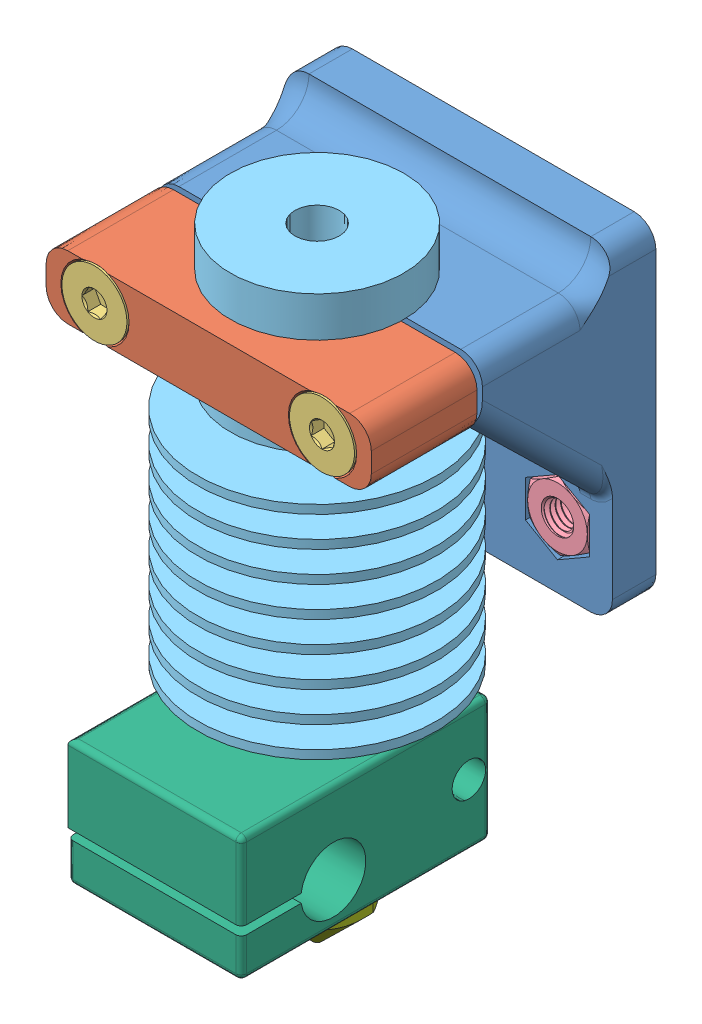
SolidWorks assembly Hotend Mount Assem, configuration Default . Lengths in mm.
Overall size (30 57.2 31.25).
11 component instances, 7 part files, 24 mates.
Components (placement in the parent):
- RearPart-1: RearPart [Default] at origin size (30 30 16)
- FrontPart-1: FrontPart [Default] at (0 9.075 21.375) size (30 5.85 9.75)
- M3x25 92125A138_TYPE 18-8 SS FLAT-HEAD SOCKET CAP SCREW-1: M3x25 92125A138_TYPE 18-8 SS FLAT-HEAD SOCKET CAP SCREW [92125A138] at (-10.4974 9.075 26.3) x (-0.848151 0.529754 0) z (0 0 1)
- M3x25 92125A138_TYPE 18-8 SS FLAT-HEAD SOCKET CAP SCREW-2: M3x25 92125A138_TYPE 18-8 SS FLAT-HEAD SOCKET CAP SCREW [92125A138] at (10.4974 9.075 26.3)
- 94150A325_TYPE 316 STAINLESS STEEL HEX NUT-1: 94150A325_TYPE 316 STAINLESS STEEL HEX NUT [94150A325] at (10.4974 9.075 3.8) x (0.5 -0.866025 0) z (0 0 1)
- 94150A325_TYPE 316 STAINLESS STEEL HEX NUT-2: 94150A325_TYPE 316 STAINLESS STEEL HEX NUT [94150A325] at (-10.4974 9.075 3.8)
- Lite6HeatSink-1: Lite6HeatSink [Default] at (0 -5.65 16.25) size (22 42.7 22)
- 94150A325_TYPE 316 STAINLESS STEEL HEX NUT-3: 94150A325_TYPE 316 STAINLESS STEEL HEX NUT [94150A325] at (9.925 -8.95 2.8)
- 94150A325_TYPE 316 STAINLESS STEEL HEX NUT-4: 94150A325_TYPE 316 STAINLESS STEEL HEX NUT [94150A325] at (-9.925 -8.95 2.8) x (0.5 0.866025 0) z (0 0 1)
- Heater Block-1: Heater Block [Default] at (0 -33.5 19.75) x (0 0 -1) z (1 0 0) size (23 11.5 16)
- MK8 nozzle 0,4mm-2: MK8 nozzle 0,4mm [Default] at (0 -33.5 16.25) x (-0.795741 0 0.605637) z (0.605637 0 0.795741)
Mates (geometry in assembly coordinates):
- Concentric1: concentric aligned: cylinder of RearPart-1 through (0 28.9706 16.25) axis (0 -1 0) radius 6; cylinder of FrontPart-1 through (0 12 16.25) axis (0 -1 0) radius 6
- Concentric2: concentric aligned: cylinder of RearPart-1 through (10.4974 9.075 16) axis (0 0 1) radius 1.8; cylinder of FrontPart-1 through (10.4974 9.075 26.25) axis (0 0 1) radius 1.8
- Coincident5: coincident aligned: cone of FrontPart-1 through (-10.4974 9.075 26.25) axis (0 0 -1); cone of M3x25 92125A138_TYPE 18-8 SS FLAT-HEAD SOCKET CAP SCREW-1 through (-10.4974 9.075 24.6) axis (0 0 -1)
- Coincident6: coincident aligned: cone of FrontPart-1 through (10.4974 9.075 26.25) axis (0 0 -1); cone of M3x25 92125A138_TYPE 18-8 SS FLAT-HEAD SOCKET CAP SCREW-2 through (10.4974 9.075 24.6) axis (0 0 -1)
- Concentric5: concentric anti-aligned: circle of RearPart-1; circle of 94150A325_TYPE 316 STAINLESS STEEL HEX NUT-1
- Coincident7: coincident anti-aligned: plane of RearPart-1 through (0 0 5) normal (0 0 -1); plane of 94150A325_TYPE 316 STAINLESS STEEL HEX NUT-1 through (10.4974 12.2504 5) normal (0 0 1)
- Parallel1: parallel anti-aligned: plane of RearPart-1 through (13.4474 10.7782 5) normal (-0.5 -0.866025 0); plane of 94150A325_TYPE 316 STAINLESS STEEL HEX NUT-1 through (13.2474 10.6627 5) normal (0.5 0.866025 0)
- Concentric6: concentric anti-aligned: circle of 92125A138_TYPE 18-8 SS FLAT-HEAD SOCKET CAP SCREW-1; circle of 94150A325_TYPE 316 STAINLESS STEEL HEX NUT-2
- Coincident8: coincident anti-aligned: plane of RearPart-1 through (0 0 5) normal (0 0 -1); plane of 94150A325_TYPE 316 STAINLESS STEEL HEX NUT-2 through (-13.2474 10.6627 5) normal (0 0 1)
- Parallel2: parallel anti-aligned: plane of RearPart-1 through (-13.4474 10.7782 5) normal (0.5 -0.866025 0); plane of 94150A325_TYPE 316 STAINLESS STEEL HEX NUT-2 through (-10.4974 12.2504 5) normal (-0.5 0.866025 0)
- Concentric7: concentric aligned: cylinder of RearPart-1 through (0 28.9706 16.25) axis (0 -1 0) radius 6; cylinder of Lite6HeatSink-1 through (0 -27 16.25) axis (0 -1 0) radius 6
- Coincident9: coincident anti-aligned: plane of RearPart-1 through (0 12 16) normal (0 1 0); plane of Lite6HeatSink-1 through (8 12 16.25) normal (0 -1 0)
- Concentric9: concentric anti-aligned: cylinder of RearPart-1 through (9.925 -8.95 4) axis (0 0 1) radius 1.8; circle of 94150A325_TYPE 316 STAINLESS STEEL HEX NUT-3
- Parallel3: parallel anti-aligned: plane of 94150A325_TYPE 316 STAINLESS STEEL HEX NUT-3 through (12.675 -7.3623 4) normal (0.5 0.866025 0); plane of RearPart-1 through (0.0808 0.1399 1.6) normal (-0.5 -0.866025 0)
- Coincident11: coincident anti-aligned: plane of RearPart-1 through (0 0 1.6) normal (0 0 1); plane of 94150A325_TYPE 316 STAINLESS STEEL HEX NUT-3 through (7.175 -7.3623 1.6) normal (0 0 -1)
- Concentric10: concentric anti-aligned: cylinder of RearPart-1 through (-9.925 -8.95 4) axis (0 0 1) radius 1.8; circle of 94150A325_TYPE 316 STAINLESS STEEL HEX NUT-4
- Parallel4: parallel anti-aligned: plane of 94150A325_TYPE 316 STAINLESS STEEL HEX NUT-4 through (-9.925 -5.7746 4) normal (-0.5 0.866025 0); plane of RearPart-1 through (-0.0808 0.1399 1.6) normal (0.5 -0.866025 0)
- Coincident12: coincident anti-aligned: plane of RearPart-1 through (0 0 1.6) normal (0 0 1); plane of 94150A325_TYPE 316 STAINLESS STEEL HEX NUT-4 through (-12.675 -10.5377 1.6) normal (0 0 -1)
- Concentric11: concentric aligned: circle of Lite6HeatSink-1; circle of Heater Block-1
- Parallel5: parallel aligned: plane of RearPart-1 through (0 0 0) normal (0 0 -1); plane of Heater Block-1 through (8 -22 8.25) normal (0 0 -1)
- Concentric12: concentric anti-aligned: circle of Heater Block-1; circle of MK8 nozzle 0,4mm-2
- Coincident14: coincident anti-aligned: plane of Heater Block-1 through (0 -33.5 19.75) normal (0 -1 0); plane of MK8 nozzle 0,4mm-2 through (0 -33.5 16.25) normal (0 1 0)
- Coincident15: coincident aligned: plane of Lite6HeatSink-1 through (3.2 -22 16.25) normal (0 1 0); plane of Heater Block-1 through (0 -22 19.75) normal (0 1 0)
- Parallel6: parallel aligned: plane of Lite6HeatSink-1 through (0 -5.65 16.25) normal (0 0 1)
